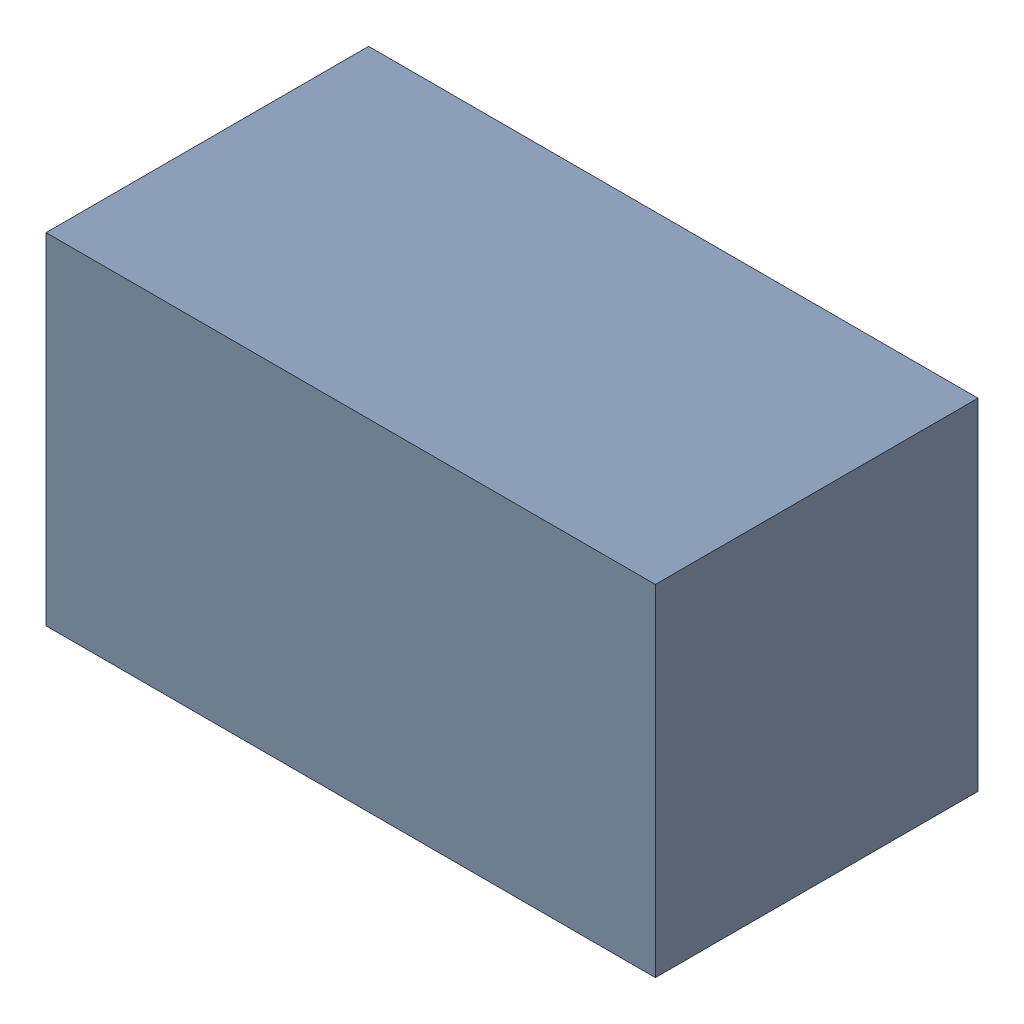
SolidWorks assembly D2, configuration Default. Lengths in mm.
Overall size (1.7 0.95 0.9).
2 component instances, 1 part files, 0 mates.
Components (placement in the parent):
- 580483600-1: 580483600 [Default] at (276.237 286.385 0) size (1.7 0.95 0.9)
  - Extruded_3-1: Extruded_3 [Default] at origin size (1.7 0.95 0.9)
